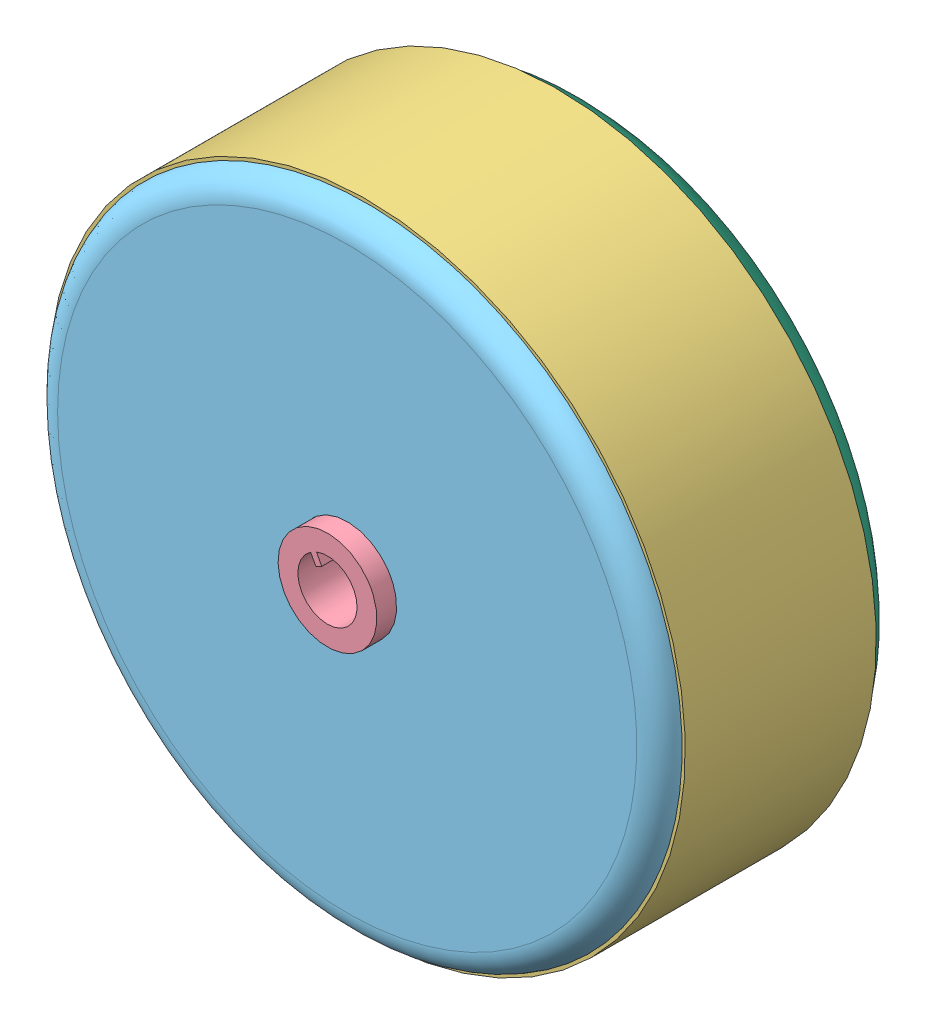
SolidWorks assembly cicloidal completo, configuration Default. Lengths in mm.
Overall size (136.71 136.71 65).
7 component instances, 6 part files, 14 mates.
Components (placement in the parent):
- cycloid gear -1: cycloid gear  [Default] at (-150.6159 50.1234 -123.5782) x (0.341897 -0.939737 0) z (0 0 1) size (86.94 87.15 4)
- outputmech-1: outputmech [Default] at (-149.7874 50.5674 -123.5782) x (0.272727 0.962091 0) z (0 0 1) size (81.5 81.5 60)
- pingear-1: pingear [Default] at (-149.7874 50.5674 -133.5782) x (0.687959 0.725749 0) z (0 0 1) size (96.7 96.7 29)
- inputmech-1: inputmech [Default] at (-150.6159 50.1234 -123.5782) x (0.881402 0.472367 0) z (0 0 1) size (58.68 56.8 25)
- cycloid gear -2: cycloid gear  [Default] at (-148.9589 51.0114 -113.5782) x (0.185697 0.982607 0) z (0 0 1) size (86.94 87.15 4)
- tapa input-2: tapa input [Default] at (-149.7874 50.5674 -104.5782) x (0.306763 0.951786 0) z (0 0 1) size (95.7 95.7 3)
- tapa output-2: tapa output [Default] at (-149.7874 50.5674 -139.5782) size (95.7 95.7 6)
Mates (geometry in assembly coordinates):
- Concentric1: concentric anti-aligned: cylinder of inputmech-1 through (-148.9589 51.0114 -109.5782) axis (0 0 -1) radius 28.4; cylinder of cycloid gear -2 through (-148.9589 51.0114 -113.5782) axis (0 0 1) radius 28.4
- Coincident1: coincident aligned: plane of inputmech-1 through (-148.9589 51.0114 -109.5782) normal (0 0 1); plane of cycloid gear -2 through (-190.9082 58.5091 -109.5782) normal (0 0 1)
- Concentric2: concentric anti-aligned: cylinder of cycloid gear -1 through (-150.6159 50.1234 -123.5782) axis (0 0 1) radius 28.4; cylinder of inputmech-1 through (-150.6159 50.1234 -116.5782) axis (0 0 -1) radius 28.4
- Coincident2: coincident aligned: plane of cycloid gear -1 through (-110.7162 65.0895 -123.5782) normal (0 0 -1); plane of inputmech-1 through (-150.6159 50.1234 -123.5782) normal (0 0 -1)
- Concentric7: concentric aligned: circle of outputmech-1; circle of pingear-1
- Concentric11: concentric anti-aligned: cylinder of inputmech-1 through (-149.7874 50.5674 -98.5782) axis (0 0 -1) radius 7.5; cylinder of tapa input-2 through (-149.7874 50.5674 -107.5782) axis (0 0 1) radius 7.5
- Concentric13: concentric aligned: cylinder of outputmech-1 through (-149.7874 50.5674 -163.5782) axis (0 0 1) radius 5; cylinder of tapa output-2 through (-149.7874 50.5674 -139.5782) axis (0 0 1) radius 14.235
- Coincident6: coincident anti-aligned: plane of outputmech-1 through (-149.7874 50.5674 -133.5782) normal (0 0 -1); plane of tapa output-2 through (-149.7874 50.5674 -133.5782) normal (0 0 1)
- Coincident10: coincident anti-aligned: plane of outputmech-1 through (-149.7874 50.5674 -123.5782) normal (0 0 1); plane of inputmech-1 through (-150.6159 50.1234 -123.5782) normal (0 0 -1)
- Concentric17: concentric aligned: circle of inputmech-1; circle of tapa output-2
- Concentric18: concentric anti-aligned: circle of pingear-1; circle of tapa output-2
- Coincident11: coincident anti-aligned: plane of pingear-1 through (-149.7874 50.5674 -133.5782) normal (0 0 -1); plane of tapa output-2 through (-149.7874 50.5674 -133.5782) normal (0 0 1)
- Concentric19: concentric anti-aligned: circle of pingear-1; circle of tapa input-2
- Coincident12: coincident anti-aligned: plane of pingear-1 through (-149.7874 50.5674 -104.5782) normal (0 0 1); plane of tapa input-2 through (-149.7874 50.5674 -104.5782) normal (0 0 -1)
